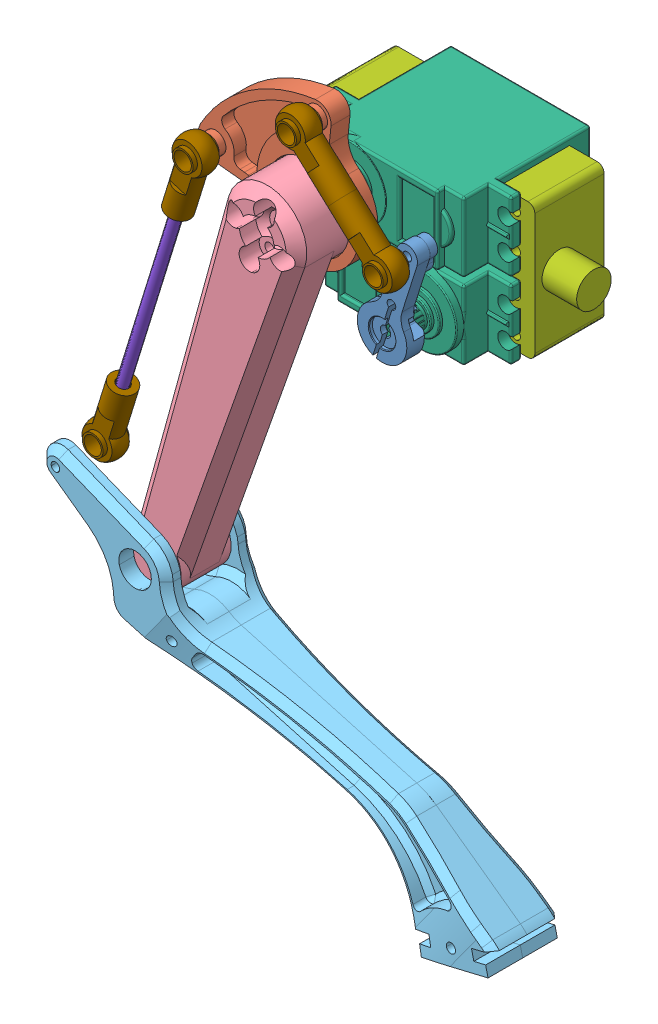
SolidWorks assembly test_rhs, configuration Default. Lengths in mm.
Overall size (153.34 219.79 97.38).
14 component instances, 9 part files, 37 mates.
Components (placement in the parent):
- link3_m-1: link3_m [Default] at (165.2915 -70.5223 -57.419) x (0.2588 0.115793 0.958965) z (-0.408408 0.912799 0) size (12.82 26.51 28.54)
- joint_r-1: joint_r [Default] at (37.2265 -21.5678 91.6379) x (-0.191421 0.20915 -0.958965) z (0.737681 0.675149 0) size (17.1 41.56 44.87)
- circular_horn-1: circular_horn [Default] at (94.008 47.6959 16.4844) x (0.781397 0.624034 0) z (-0.624034 0.781397 0) size (20 4.5 20)
- upperleg-1: upperleg [Default] at (125.7049 -36.0711 -55.669) x (0.248176 0.137092 0.958965) z (-0.483529 0.875328 0) size (39.1 93.25 88.61)
- lowerleg_r-1: lowerleg_r [Default] at (28.2755 3.596 108.1379) x (-0.081842 0.271454 -0.958965) z (0.957432 0.28866 0) size (46.27 106.28 105.17)
- Servo MG996R-1: Servo MG996R [Predeterminado] at (84.008 37.6959 -33.1156) x (1 0 0) z (0 -1 0) size (53.6 47.6 20)
- m_servo_siding-1: m_servo_siding [Default] at (129.808 36.6959 -26.5156) size (20 39 20)
- Servo MG996R-2: Servo MG996R [Predeterminado] at (124.308 35.6959 -33.1156) x (-1 0 0) z (0 1 0) size (53.6 47.6 20)
- m_servo_siding-2: m_servo_siding [Default] at (78.508 36.6959 -26.5156) x (-1 0 0) z (0 0 1) size (20 39 20)
- 74_thread-1: 74_thread [Default] at (43.2332 -26.9093 23.7344) x (0.955407 -0.295291 0) z (0 0 1) size (3 74 3)
- ball_joint-1: ball_joint [Default] at (67.1518 50.4787 23.7344) x (0.955407 -0.295291 0) z (0 0 1) size (10 22 7.5)
- ball_joint-2: ball_joint [Default] at (41.1662 -33.5971 23.7344) x (0.955407 -0.295291 0) z (0 0 -1) size (10 22 7.5)
- ball_joint-3: ball_joint [Default] at (96.4816 71.5681 23.2344) x (0.676058 0.736848 0) z (0 0 1) size (10 22 7.5)
- ball_joint-4: ball_joint [Default] at (121.5344 48.5821 23.2344) x (0.676058 0.736848 0) z (0 0 -1) size (10 22 7.5)
Mates (geometry in assembly coordinates):
- Concentric2: concentric anti-aligned: cylinder of link3_m-1 through (121.5344 48.5821 13.4344) axis (0 0 1) radius 3; cylinder of link2_m-1 through (119.1735 49.1975 23.0844) axis (0 0 -1) radius 3.5
- Coincident7: coincident anti-aligned: plane of link3_m-1 through (121.5344 48.5821 17.0844) normal (0 0 1); plane of link2_m-1 through (93.6799 71.6937 17.0844) normal (0 0 -1)
- Concentric4: concentric anti-aligned: cylinder of joint_r-1 through (94.008 47.6959 30.0698) axis (0 0 -1) radius 4.625; cylinder of circular_horn-1 through (94.008 47.6959 14.4844) axis (0 0 1) radius 10
- Coincident9: coincident anti-aligned: plane of joint_r-1 through (94.008 47.6959 14.4844) normal (0 0 1); plane of circular_horn-1 through (94.008 47.6959 14.4844) normal (0 0 -1)
- Concentric5: concentric anti-aligned: cylinder of circular_horn-1 through (94.008 47.6959 14.4844) axis (0 0 1) radius 1.5; cylinder of upperleg-1 through (94.008 47.6959 32.9844) axis (0 0 -1) radius 11.5
- Coincident10: coincident anti-aligned: plane of joint_r-1 through (94.008 47.6959 14.4844) normal (0 0 1); plane of upperleg-1 through (94.008 47.6959 14.4844) normal (0 0 -1)
- Concentric6: concentric aligned: cylinder of joint_r-1 through (67.1518 50.4787 30.0698) axis (0 0 -1) radius 1.35; cylinder of link1_m-1 through (68.2902 55.9176 33.9844) axis (0 0 -1) radius 3.5
- Concentric7: concentric aligned: cylinder of upperleg-1 through (64.1619 -47.7463 18.4844) axis (0 0 -1) radius 1.85; cylinder of lowerleg_r-1 through (64.1619 -47.7463 38.9692) axis (0 0 -1) radius 4.7
- Width1: width aligned: plane of lowerleg_r-1 through (64.1619 -47.7463 17.4844) normal (0 0 1); plane of lowerleg_r-1 through (64.1619 -47.7463 33.9844) normal (0 0 -1); plane of upperleg-1 through (94.008 47.6959 32.9844) normal (0 0 1); plane of upperleg-1 through (94.008 47.6959 18.4844) normal (0 0 -1)
- Concentric8: concentric aligned: cylinder of link1_m-1 through (50.5605 -36.3952 33.9844) axis (0 0 -1) radius 3.5; cylinder of lowerleg_r-1 through (41.1662 -33.5971 75.18) axis (0 0 -1) radius 1.25
- Coincident11: coincident anti-aligned: plane of link1_m-1 through (50.5605 -36.3952 33.9844) normal (0 0 1); plane of lowerleg_r-1 through (64.1619 -47.7463 33.9844) normal (0 0 -1)
- Concentric9: concentric aligned: cylinder of link2_m-1 through (93.6799 71.6937 23.0844) axis (0 0 -1) radius 3.5; cylinder of joint_r-1 through (96.4816 71.5681 29.3249) axis (0 0 -1) radius 1.35
- Concentric10: concentric aligned: cylinder of Servo MG996R-1 through (129.308 52.1959 -6.5156) axis (0 0 1) radius 2.22; cylinder of m_servo_siding-1 through (129.308 52.1959 -18.5156) axis (0 0 1) radius 1.35
- Parallel1: parallel aligned: plane of Servo MG996R-1 through (84.008 57.6959 3.4844) normal (0 1 0); plane of m_servo_siding-1 through (124.808 56.1959 -6.5156) normal (0 1 0)
- Coincident12: coincident anti-aligned: plane of Servo MG996R-1 through (130.958 37.6959 -6.5156) normal (0 0 -1); plane of m_servo_siding-1 through (132.808 54.1959 -6.5156) normal (0 0 1)
- Coincident14: coincident anti-aligned: plane of m_servo_siding-1 through (132.808 54.1959 -6.5156) normal (0 0 1); plane of Servo MG996R-2 through (77.358 35.6959 -6.5156) normal (0 0 -1)
- Concentric12: concentric aligned: cylinder of Servo MG996R-1 through (79.008 52.1959 -6.5156) axis (0 0 1) radius 2.22; cylinder of m_servo_siding-2 through (79.008 52.1959 -18.5156) axis (0 0 1) radius 1.35
- Coincident15: coincident anti-aligned: plane of Servo MG996R-1 through (77.358 37.6959 -6.5156) normal (0 0 -1); plane of m_servo_siding-2 through (75.508 19.1959 -6.5156) normal (0 0 1)
- Concentric14: concentric aligned: cylinder of m_servo_siding-1 through (129.308 21.1959 -18.5156) axis (0 0 1) radius 1.35; cylinder of Servo MG996R-2 through (129.308 21.1959 -6.5156) axis (0 0 1) radius 2.22
- Coincident16: coincident aligned: plane of Servo MG996R-1 through (124.308 37.6959 3.4844) normal (1 0 0); plane of Servo MG996R-2 through (124.308 35.6959 3.4844) normal (1 0 0)
- Concentric15: concentric aligned: cylinder of Servo MG996R-2 through (79.008 21.1959 -6.5156) axis (0 0 1) radius 2.22; cylinder of m_servo_siding-2 through (79.008 21.1959 -18.5156) axis (0 0 1) radius 1.35
- Concentric16: concentric aligned: cylinder of link3_m-1 through (114.308 25.6959 24.1789) axis (0 0 -1) radius 1.5; cylinder of Servo MG996R-2 through (114.308 25.6959 14.4844) axis (0 0 -1) radius 3.592
- Coincident17: coincident anti-aligned: plane of link3_m-1 through (114.308 25.6959 14.4844) normal (0 0 -1); plane of Servo MG996R-2 through (114.308 25.6959 14.4844) normal (0 0 1)
- Concentric17: concentric aligned: cylinder of upperleg-1 through (94.008 47.6959 31.4629) axis (0 0 -1) radius 5; cylinder of Servo MG996R-1 through (94.008 47.6959 14.4844) axis (0 0 -1) radius 3.592
- Coincident18: coincident anti-aligned: plane of circular_horn-1 through (94.008 47.6959 14.4844) normal (0 0 -1); plane of Servo MG996R-1 through (94.008 47.6959 14.4844) normal (0 0 1)
- Concentric18: concentric aligned: cylinder of 74_thread-1 through (65.0848 43.7909 23.7344) axis (-0.295291 -0.955407 0) radius 1.5; cylinder of ball_joint-1 through (67.1518 50.4787 23.7344) axis (-0.295291 -0.955407 0) radius 3.5
- Coincident19: coincident anti-aligned: plane of 74_thread-1 through (65.0848 43.7909 23.7344) normal (0.295291 0.955407 0); plane of ball_joint-1 through (65.0848 43.7909 23.7344) normal (-0.295291 -0.955407 0)
- Concentric19: concentric anti-aligned: cylinder of 74_thread-1 through (65.0848 43.7909 23.7344) axis (-0.295291 -0.955407 0) radius 1.5; cylinder of ball_joint-2 through (41.1662 -33.5971 23.7344) axis (0.295291 0.955407 0) radius 1.75
- Coincident20: coincident anti-aligned: plane of 74_thread-1 through (43.2332 -26.9093 23.7344) normal (-0.295291 -0.955407 0); plane of ball_joint-2 through (43.2332 -26.9093 23.7344) normal (0.295291 0.955407 0)
- Coincident21: coincident anti-aligned: plane of ball_joint-3 through (110.1911 61.3646 23.2344) normal (0.736848 -0.676058 0); plane of ball_joint-4 through (110.1911 61.3646 23.2344) normal (-0.736848 0.676058 0)
- Concentric20: concentric anti-aligned: cylinder of ball_joint-3 through (96.4816 71.5681 23.2344) axis (0.736848 -0.676058 0) radius 3.5; cylinder of ball_joint-4 through (121.5344 48.5821 23.2344) axis (-0.736848 0.676058 0) radius 3.5
- Concentric21: concentric aligned: cylinder of lowerleg_r-1 through (41.1662 -33.5971 75.18) axis (0 0 -1) radius 1.25; cylinder of ball_joint-2 through (41.1662 -33.5971 28.7344) axis (0 0 -1) radius 2.5
- Concentric23: concentric anti-aligned: cylinder of joint_r-1 through (67.1518 50.4787 30.0698) axis (0 0 -1) radius 1.35; cylinder of ball_joint-1 through (67.1518 50.4787 18.7344) axis (0 0 1) radius 2.5
- Coincident22: coincident anti-aligned: plane of joint_r-1 through (67.1518 50.4787 19.9844) normal (0 0 1); plane of ball_joint-1 through (67.1518 50.4787 19.9844) normal (0 0 -1)
- Concentric24: concentric anti-aligned: cylinder of joint_r-1 through (96.4816 71.5681 29.3249) axis (0 0 -1) radius 1.35; cylinder of ball_joint-3 through (96.4816 71.5681 18.2344) axis (0 0 1) radius 2.5
- Coincident23: coincident anti-aligned: plane of joint_r-1 through (96.4816 71.5681 19.4844) normal (0 0 1); plane of ball_joint-3 through (96.4816 71.5681 19.4844) normal (0 0 -1)
- Concentric25: concentric anti-aligned: cylinder of link3_m-1 through (121.5344 48.5821 4.3655) axis (0 0 1) radius 1.25; cylinder of ball_joint-4 through (121.5344 48.5821 28.2344) axis (0 0 -1) radius 2.5
